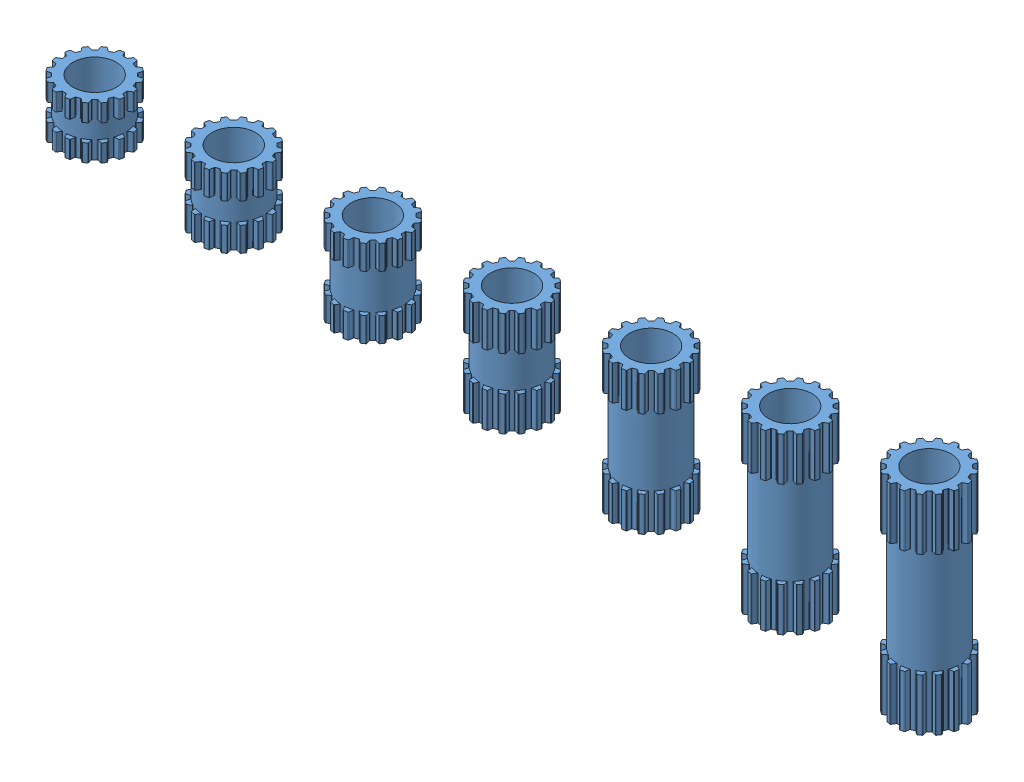
SolidWorks assembly Assembly of M3 X 3-12  mm Length, Brass Knurled Inserts, configuration Default. Lengths in mm.
Overall size (51.96 12 3.96).
7 component instances, 1 part files, 1 mates.
Components (placement in the parent):
- M3 X 3-12  mm Length, Brass Knurled Insert-1: M3 X 3-12  mm Length, Brass Knurled Insert [3 mm] at origin size (3.96 3 3.96)
- M3 X 3-12  mm Length, Brass Knurled Insert-2: M3 X 3-12  mm Length, Brass Knurled Insert [4 mm] at (8 0 0) size (3.96 4 3.96)
- M3 X 3-12  mm Length, Brass Knurled Insert-3: M3 X 3-12  mm Length, Brass Knurled Insert [5 mm] at (16 0 0) size (3.96 5 3.96)
- M3 X 3-12  mm Length, Brass Knurled Insert-4: M3 X 3-12  mm Length, Brass Knurled Insert [6 mm] at (24 0 0) size (3.96 6 3.96)
- M3 X 3-12  mm Length, Brass Knurled Insert-5: M3 X 3-12  mm Length, Brass Knurled Insert [8 mm] at (32 0 0) size (3.96 8 3.96)
- M3 X 3-12  mm Length, Brass Knurled Insert-6: M3 X 3-12  mm Length, Brass Knurled Insert [10 mm] at (40 0 0) size (3.96 10 3.96)
- M3 X 3-12  mm Length, Brass Knurled Insert-7: M3 X 3-12  mm Length, Brass Knurled Insert [12 mm] at (48 0 0) size (3.96 12 3.96)
Mates (geometry in assembly coordinates):
- Coincident1: coordinate: point of assembly; point of M3 X 3-12  mm Length, Brass Knurled Insert-1; point of assembly
